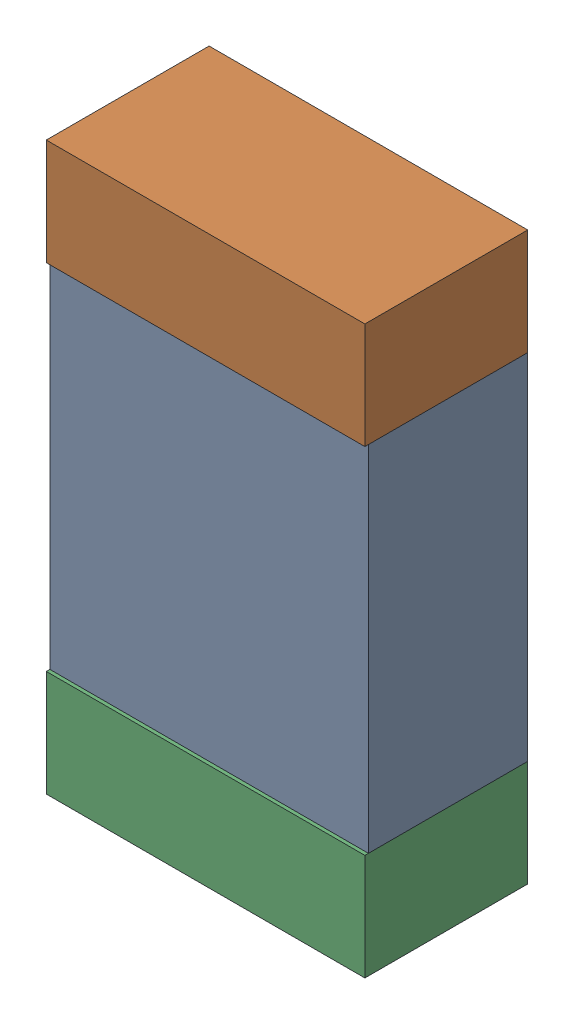
SolidWorks assembly L6, configuration Default. Lengths in mm.
Overall size (0.9 1.6 0.46).
6 component instances, 2 part files, 0 mates.
Components (placement in the parent):
- 870944160-1: 870944160 [Default] at (67.36 45.032 0) size (0.9 1 0.45)
  - Extruded_25-1: Extruded_25 [Default] at origin size (0.9 1 0.45)
- 870944320-1: 870944320 [Default] at (67.36 45.682 0) size (0.9 0.3 0.46)
  - Extruded_26-1: Extruded_26 [Default] at origin size (0.9 0.3 0.46)
- 870944320-2: 870944320 [Default] at (67.36 44.382 0) size (0.9 0.3 0.46)
  - Extruded_26-1: Extruded_26 [Default] at origin size (0.9 0.3 0.46)
